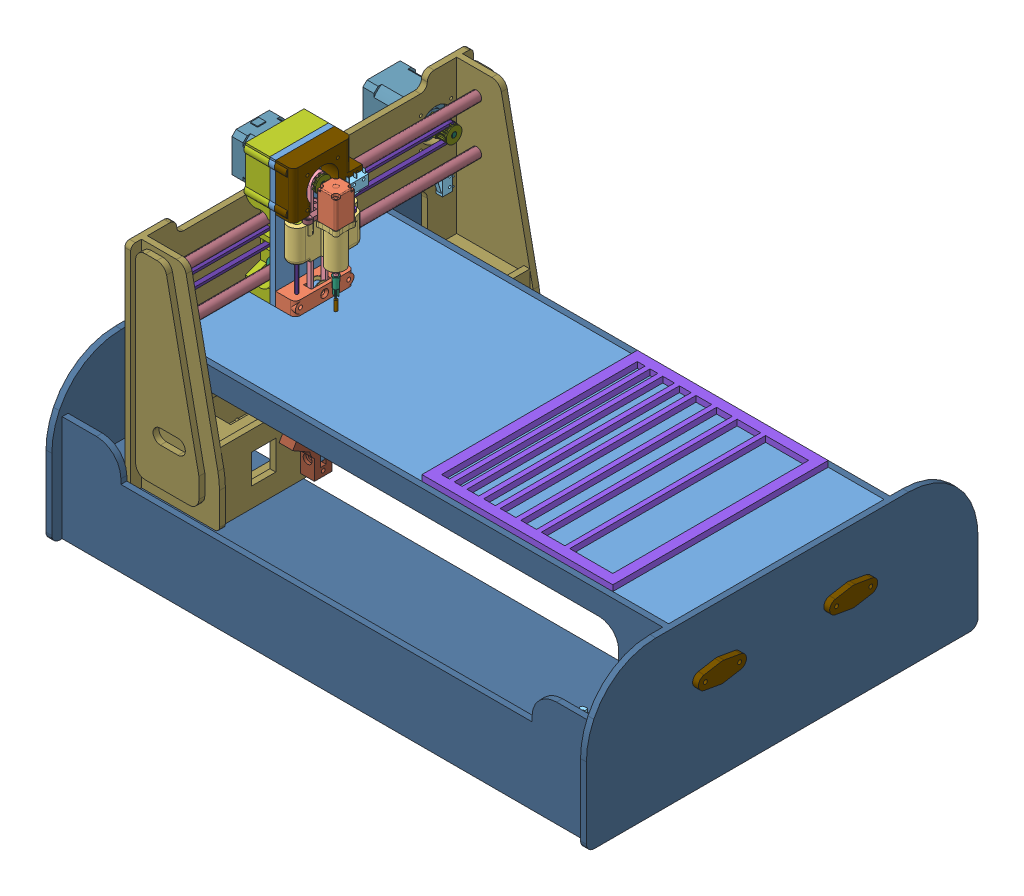
SolidWorks assembly Complete development assy, configuration По умолчанию. Lengths in mm.
Overall size (564 317.3 400).
83 component instances, 37 part files, 132 mates.
Components (placement in the parent):
- Y carret base-1: Y carret base [По умолчанию] at (-34.4349 94.3 -77.1214) x (0 0 -1) z (1 0 0) size (71.9 130 6)
- Vacuum manipulator-1: Vacuum manipulator [По умолчанию] at (13.1651 129.9 -77.1214) x (0 0 -1) z (1 0 0) size (60 110 38.83)
  - FL20STH30-0604A-1: FL20STH30-0604A [По умолчанию] at (0 10.1 -10.1) x (1 0 0) z (0 -1 0) size (20.2 20.2 45)
  - Vacuum connector-1: Vacuum connector [По умолчанию] at (0 -19.9 -10.1) x (1 0 0) z (0 0 -1) size (60 40 38.83)
  - Vacuum manipulator axis-1: Vacuum manipulator axis [По умолчанию] at (0 -39.1192 -10.1) x (0.991916 0 0.126893) z (-0.126893 0 0.991916) size (13 52.5 13)
  - Silicone gasket-1: Silicone gasket [По умолчанию] at (0 -39.9 -10.1) x (0.962843 0 -0.270063) z (0 1 0) size (13 13 5)
  - Silicone gasket-2: Silicone gasket [По умолчанию] at (0 -54.9 -10.1) x (0.992934 0 -0.118668) z (0 1 0) size (13 13 5)
  - Syringe needle-1: Syringe needle [По умолчанию] at (0 -68.4 -10.1) x (0.516653 0 0.856195) z (-0.856195 0 0.516653) size (6.5 31 6.5)
  - PTFE Z bushing-1: PTFE Z bushing [По умолчанию] at (-21 -53.9 -29.1) x (1 0 0) z (0 1 0) size (8 8 34)
  - PTFE Z bushing-2: PTFE Z bushing [По умолчанию] at (21 -53.9 -29.1) x (1 0 0) z (0 1 0) size (8 8 34)
  - Vacuum connectoe union-1: Vacuum connectoe union [По умолчанию] at (16 -7.4 -10.1) x (1 0 0) z (0 -1 0) size (7 7 25)
  - Silicone cap-1: Silicone cap [По умолчанию] at (0 -99.9 -10.1) x (1 0 0) z (0 1 0) size (3 3 10)
  - Vacoom connector fixing washer-2: Vacoom connector fixing washer [По умолчанию] at (0 -59.9 -10.1) x (0.897919 0 -0.440161) z (0 1 0) size (13 13 5)
  - Z belt spring-1: Z belt spring [По умолчанию] at (-7.25 -34.9 -29.1) x (0.706502 0 0.707711) z (0 -1 0) size (11.12 11.15 15.02)
  - Belt fixer-1: Belt fixer [По умолчанию] at (-7.25 -34.9 -29.1) x (-0.144268 0 -0.989539) z (0 1 0) size (11 11 15)
  - Vacoom connector cup-1: Vacoom connector cup [По умолчанию] at (-5.75 -15.9 -29.6632) x (1 0 0) z (0 -1 0) size (25.79 19.09 4)
- FL42-motor-1: FL42-motor [Default] at (-85.9269 135.15 -77.1214) x (0 0 -1) z (1 0 0) size (42.3 43.3 72)
  - FL42-1: FL42 [Default] at (-21.15 -21.15 3.992) size (42.3 43.3 49.5)
  - FL42-axis-1: FL42-axis [Default] at (0 0 31.992) size (5 5 44)
- belt pulley - hex base10-1: belt pulley - hex base10 [По умолчанию] at (-17.9349 135.15 -77.1214) x (0 0 -1) z (1 0 0) size (16 18.48 22.5)
- 3х86 rod-1: 3х86 rod [По умолчанию] at (-15.9349 122 -56.1214) x (0.06465 0 -0.997908) z (0 -1 0) size (3 3 86)
- 3х86 rod-2: 3х86 rod [По умолчанию] at (-15.9349 122 -98.1214) x (-0.993278 0 0.115757) z (0 -1 0) size (3 3 86)
- Z carret rod top fixer-1: Z carret rod top fixer [По умолчанию] at (-28.4349 131.8 -77.1214) x (0 0 -1) z (1 0 0) size (71.9 50 18)
- radial ball bearing_68_din-1: radial ball bearing_68_din [DIN 625 - 624 - 8,SI,NC,8_68] at (-15.9349 39.3 -77.1214) x (-1 0 0) z (0 -0.797158 -0.603771) size (5 13 13)
- Z carret rod bottom fixer-1: Z carret rod bottom fixer [По умолчанию] at (-28.4349 39.3 -77.1214) x (0 0 -1) z (1 0 0) size (60 14 20)
- Bearing washer-1: Bearing washer [По умолчанию] at (-11.9349 39.3 -77.1214) x (0 -0.383049 0.923728) z (-1 0 0) size (18 18 1.5)
- Bearing washer-2: Bearing washer [По умолчанию] at (-19.9349 39.3 -77.1214) x (0 0 -1) z (1 0 0) size (18 18 1.5)
- Z belt-1: Z belt [По умолчанию] at (-18.1849 89.225 -77.1214) x (0 0 -1) z (1 0 0) size (17 108.85 4.5)
- microswitch standin-1: microswitch standin [Default] at (-7.1849 127.3 -107.6214) x (1 0 0) z (0 0 -1) size (6.5 24.49 20.19)
- LM10UU-1: LM10UU [По умолчанию] at (-43.9349 51 -77.1214) x (-0.203502 -0.979074 0) z (-0.979074 0.203502 0) size (19 29 19)
- LM10UU-2: LM10UU [По умолчанию] at (-43.9349 101 -77.1214) x (-0.767518 0.641027 0) z (0.641027 0.767518 0) size (19 29 19)
- Y carret bearing fixer-1: Y carret bearing fixer [По умолчанию] at (-59.4349 97.3 -77.1214) x (0 0 -1) z (1 0 0) size (62.8 130 28)
- Cassete-1: Cassete [По умолчанию] at (292.0651 0 -110) x (0 0 -1) z (0 1 0) size (220 195 6)
- 16mm tube rod-1: 16mm tube rod [По умолчанию] at (426.0651 -58.2762 -177) x (0 -0.995748 -0.092117) z (-1 0 0) size (16 16 552)
- 16mm tube rod-2: 16mm tube rod [По умолчанию] at (426.0651 -58.2762 -43) x (0 0.422932 0.906162) z (-1 0 0) size (16 16 552)
- Base frame-1: Base frame [По умолчанию] at (204.0651 -12 -110) size (552 155 400)
- 16mm  printable linear bearing-1: 16mm  printable linear bearing [По умолчанию] at (-44.9682 -60.9468 -172.6484) x (0 0 1) z (1 0 0) size (62.22 53.88 14)
  - Bearing frame-1: Bearing frame [По умолчанию] at (-4.3516 -2.6706 55.2152) size (62.22 53.88 14)
  - radial ball bearing_68_din-1: radial ball bearing_68_din [DIN 625 - 624 - 8,SI,NC,8_68] at (-16.909 -9.9206 62.2152) x (0.5 -0.866025 0) z (0 0 1) size (5 13 13)
  - radial ball bearing_68_din-2: radial ball bearing_68_din [DIN 625 - 624 - 8,SI,NC,8_68] at (8.2057 -9.9206 62.2152) x (0.5 0.866025 0) z (0 0 1) size (5 13 13)
  - radial ball bearing_68_din-3: radial ball bearing_68_din [DIN 625 - 624 - 8,SI,NC,8_68] at (-4.3516 11.8294 62.2152) size (5 13 13)
- 16mm  printable linear bearing-2: 16mm  printable linear bearing [По умолчанию] at (-139.6501 -60.9468 -172.6484) x (0 0 1) z (1 0 0) size (62.22 53.88 14)
  - Bearing frame-1: Bearing frame [По умолчанию] at (-4.3516 -2.6706 55.2152) size (62.22 53.88 14)
  - radial ball bearing_68_din-1: radial ball bearing_68_din [DIN 625 - 624 - 8,SI,NC,8_68] at (-16.909 -9.9206 62.2152) x (0.5 -0.866025 0) z (0 0 1) size (5 13 13)
  - radial ball bearing_68_din-2: radial ball bearing_68_din [DIN 625 - 624 - 8,SI,NC,8_68] at (8.2057 -9.9206 62.2152) x (0.5 0.866025 0) z (0 0 1) size (5 13 13)
  - radial ball bearing_68_din-3: radial ball bearing_68_din [DIN 625 - 624 - 8,SI,NC,8_68] at (-4.3516 11.8294 62.2152) size (5 13 13)
- 16mm  printable linear bearing-3: 16mm  printable linear bearing [По умолчанию] at (-44.9682 -60.9468 -38.6484) x (0 0 1) z (1 0 0) size (62.22 53.88 14)
  - Bearing frame-1: Bearing frame [По умолчанию] at (-4.3516 -2.6706 55.2152) size (62.22 53.88 14)
  - radial ball bearing_68_din-1: radial ball bearing_68_din [DIN 625 - 624 - 8,SI,NC,8_68] at (-16.909 -9.9206 62.2152) x (0.5 -0.866025 0) z (0 0 1) size (5 13 13)
  - radial ball bearing_68_din-2: radial ball bearing_68_din [DIN 625 - 624 - 8,SI,NC,8_68] at (8.2057 -9.9206 62.2152) x (0.5 0.866025 0) z (0 0 1) size (5 13 13)
  - radial ball bearing_68_din-3: radial ball bearing_68_din [DIN 625 - 624 - 8,SI,NC,8_68] at (-4.3516 11.8294 62.2152) size (5 13 13)
- 16mm  printable linear bearing-4: 16mm  printable linear bearing [По умолчанию] at (-139.6501 -60.9468 -38.6484) x (0 0 1) z (1 0 0) size (62.22 53.88 14)
  - Bearing frame-1: Bearing frame [По умолчанию] at (-4.3516 -2.6706 55.2152) size (62.22 53.88 14)
  - radial ball bearing_68_din-1: radial ball bearing_68_din [DIN 625 - 624 - 8,SI,NC,8_68] at (-16.909 -9.9206 62.2152) x (0.5 -0.866025 0) z (0 0 1) size (5 13 13)
  - radial ball bearing_68_din-2: radial ball bearing_68_din [DIN 625 - 624 - 8,SI,NC,8_68] at (8.2057 -9.9206 62.2152) x (0.5 0.866025 0) z (0 0 1) size (5 13 13)
  - radial ball bearing_68_din-3: radial ball bearing_68_din [DIN 625 - 624 - 8,SI,NC,8_68] at (-4.3516 11.8294 62.2152) size (5 13 13)
- X carret-3: X carret [По умолчанию] at (-70.4349 -95 60) x (0 0 -1) z (1 0 0) size (350 220 85.68)
- FL42-motor-2: FL42-motor [Default] at (-121.9269 76 -246.85) x (0 0 1) z (1 0 0) size (42.3 43.3 72)
  - FL42-1: FL42 [Default] at (-21.15 -21.15 3.992) size (42.3 43.3 49.5)
  - FL42-axis-1: FL42-axis [Default] at (0 0 31.992) size (5 5 44)
- 10mm bar-1: 10mm bar [По умолчанию] at (-43.9349 101 -274) size (10 10 328)
- 10mm bar-2: 10mm bar [По умолчанию] at (-43.9349 51 -274) size (10 10 328)
- FL42-motor-3: FL42-motor [Default] at (398.9151 -127.992 -110) x (1 0 0) z (0 1 0) size (42.3 43.3 72)
  - FL42-1: FL42 [Default] at (-21.15 -21.15 3.992) size (42.3 43.3 49.5)
  - FL42-axis-1: FL42-axis [Default] at (0 0 31.992) size (5 5 44)
- belt pulley - hex base10-3: belt pulley - hex base10 [По умолчанию] at (398.9151 -60 -110) x (-1 0 0) z (0 1 0) size (16 18.48 22.5)
- PSU standin-1: PSU standin [Default] at (-69.9349 -129 -244.65) x (0 0 -1) z (1 0 0) size (97.7 50 200)
- Belt idler-1: Belt idler [По умолчанию] at (-64.4349 76 33.15) x (0 -1 0) z (1 0 0) size (30 16 9.9)
- Belt idler-2: Belt idler [По умолчанию] at (-92.9349 -70.5 -110) x (0 0 -1) z (0 1 0) size (30 16 9.9)
- Bearing washer-3: Bearing washer [По умолчанию] at (-92.9349 -54.1 -110) x (-0.383049 0 -0.923728) z (0 -1 0) size (18 18 1.5)
- Bearing washer-4: Bearing washer [По умолчанию] at (-48.0349 76 33.15) x (0 0.383049 -0.923728) z (-1 0 0) size (18 18 1.5)
- radial ball bearing_68_din-2: radial ball bearing_68_din [DIN 625 - 624 - 8,SI,NC,8_68] at (-52.0349 76 33.15) size (5 13 13)
- radial ball bearing_68_din-3: radial ball bearing_68_din [DIN 625 - 624 - 8,SI,NC,8_68] at (-92.9349 -58.1 -110) x (0 1 0) z (0 0 1) size (5 13 13)
- X belt-1: X belt [По умолчанию] at (152.9901 -55.85 -110) x (0 0 1) z (0 -1 0) size (17 508.85 4.5)
- belt pulley - hex base10-4: belt pulley - hex base10 [По умолчанию] at (-53.9349 76 -246.85) x (0 0 -1) z (1 0 0) size (16 18.48 22.5)
- Y belt-2: Y belt [По умолчанию] at (-49.7849 76 -106.85) x (0 -1 0) z (-1 0 0) size (17 297 4.5)
- X rod fixer-1: X rod fixer [По умолчанию] at (426.0651 -58.2762 -43) x (0 0 -1) z (1 0 0) size (49 20 6)
- X rod fixer-2: X rod fixer [По умолчанию] at (426.0651 -58.2762 -177) x (0 0 -1) z (1 0 0) size (49 20 6)
- X rod fixer-3: X rod fixer [По умолчанию] at (-125.9349 -58.2762 -177) x (0 0 1) z (-1 0 0) size (49 20 6)
- X rod fixer-4: X rod fixer [По умолчанию] at (-125.9349 -58.2762 -43) x (0 0 1) z (-1 0 0) size (49 20 6)
- microswitch standin-2: microswitch standin [Default] at (-61.1849 25 -257) x (1 0 0) z (0 -1 0) size (6.5 24.49 20.19)
- microswitch standin-3: microswitch standin [Default] at (376.0651 -94.75 33.5) x (0 1 0) z (0 0 1) size (6.5 24.49 20.19)
- Top plate-1: Top plate [По умолчанию] at (150.0651 0 -110) x (1 0 0) z (0 -1 0) size (540 220 6)
Mates (geometry in assembly coordinates):
- Расстояние2: distance = 3.5 mm anti-aligned: plane of Vacuum manipulator-1/Vacuum connector-1 through (-24.9349 50.5442 -78.8714) normal (-1 0 0); plane of Y carret base-1 through (-28.4349 94.3 -77.1214) normal (1 0 0)
- Ширина1: width anti-aligned: plane of Y carret base-1 through (-28.4349 32.3 -47.1214) normal (0 0 1); plane of Y carret base-1 through (-28.4349 32.3 -107.1214) normal (0 0 -1); cylinder of Vacuum manipulator-1/Vacuum connector-1 through (3.0651 138.2843 -77.1214) axis (0 -1 0) radius 9
- Совпадение4: coincident anti-aligned: plane of Y carret base-1 through (-34.4349 94.3 -77.1214) normal (-1 0 0); plane of FL42-motor-1/FL42-1 through (-34.4349 156.3 -55.9714) normal (1 0 0)
- Ширина2: width anti-aligned: plane of FL42-motor-1/FL42-1 through (-34.4349 114 -55.9714) normal (0 0 1); plane of FL42-motor-1/FL42-1 through (-34.4349 114 -98.2714) normal (0 0 -1); plane of Y carret base-1 through (-28.4349 32.3 -107.1214) normal (0 0 -1); plane of Y carret base-1 through (-28.4349 32.3 -47.1214) normal (0 0 1)
- Совпадение5: coincident anti-aligned: plane of FL42-motor-1/FL42-1 through (-32.4349 135.15 -77.1214) normal (1 0 0); plane of belt pulley - hex base10-1 through (-32.4349 144.3876 -77.1214) normal (-1 0 0)
- Концентричный1: concentric anti-aligned: cylinder of FL42-motor-1/FL42-axis-1 through (-9.9349 135.15 -77.1214) axis (-1 0 0) radius 2.5; cylinder of belt pulley - hex base10-1 through (-39.9302 135.15 -77.1214) axis (1 0 0) radius 2.65
- Параллельность2: parallel anti-aligned: plane of FL42-motor-1/FL42-axis-1 through (-29.9349 137.15 -78.6214) normal (0 0 -1); plane of belt pulley - hex base10-1 through (-32.4349 130.5312 -69.1214) normal (0 0 1)
- Расстояние10: distance = 6 mm aligned: plane of FL42-motor-1/FL42-1 through (-34.4349 156.3 -55.9714) normal (0 1 0); plane of Y carret base-1 through (-34.4349 162.3 -77.1214) normal (0 1 0)
- Концентричный2: concentric anti-aligned: cylinder of Vacuum manipulator-1/PTFE Z bushing-2 through (-15.9349 110 -98.1214) axis (0 -1 0) radius 1.5; cylinder of 3х86 rod-2 through (-15.9349 36 -98.1214) axis (0 1 0) radius 1.5
- Концентричный3: concentric anti-aligned: cylinder of Vacuum manipulator-1/PTFE Z bushing-1 through (-15.9349 110 -56.1214) axis (0 -1 0) radius 1.5; cylinder of 3х86 rod-1 through (-15.9349 36 -56.1214) axis (0 1 0) radius 1.5
- Совпадение11: coincident aligned: plane of 3х86 rod-1 through (-15.9349 122 -56.1214) normal (0 1 0); plane of 3х86 rod-2 through (-15.9349 122 -98.1214) normal (0 1 0)
- Совпадение13: coincident aligned: plane of Y carret base-1 through (-28.4349 32.3 -47.1214) normal (0 0 1); plane of Z carret rod top fixer-1 through (-10.4349 131.8 -47.1214) normal (0 0 1)
- Совпадение15: coincident anti-aligned: plane of Y carret base-1 through (-28.4349 94.3 -77.1214) normal (1 0 0); plane of Z carret rod top fixer-1 through (-28.4349 131.8 -77.1214) normal (-1 0 0)
- Совпадение16: coincident anti-aligned: plane of 3х86 rod-2 through (-15.9349 122 -98.1214) normal (0 1 0); plane of Z carret rod top fixer-1 through (-15.9349 122 -98.1214) normal (0 -1 0)
- Параллельность3: parallel anti-aligned: plane of Y carret base-1 through (-28.4349 94.3 -77.1214) normal (1 0 0); plane of radial ball bearing_68_din-1 through (-18.4349 43.1038 -82.1435) normal (-1 0 0)
- Ширина4: width anti-aligned: plane of Y carret base-1 through (-28.4349 32.3 -107.1214) normal (0 0 -1); plane of Y carret base-1 through (-28.4349 32.3 -47.1214) normal (0 0 1); cylinder of radial ball bearing_68_din-1 through (4.7026 39.3 -77.1214) axis (-1 0 0) radius 6.5
- Совпадение18: coincident anti-aligned: plane of Y carret base-1 through (-28.4349 94.3 -77.1214) normal (1 0 0); plane of Z carret rod bottom fixer-1 through (-28.4349 39.3 -77.1214) normal (-1 0 0)
- Совпадение19: coincident aligned: plane of Y carret base-1 through (-28.4349 32.3 -107.1214) normal (0 -1 0); plane of Z carret rod bottom fixer-1 through (-8.4349 32.3 -107.1214) normal (0 -1 0)
- Совпадение20: coincident aligned: plane of Y carret base-1 through (-28.4349 32.3 -47.1214) normal (0 0 1); plane of Z carret rod bottom fixer-1 through (-8.4349 32.3 -47.1214) normal (0 0 1)
- Расстояние3: distance = 10 mm anti-aligned: plane of radial ball bearing_68_din-1 through (-18.4349 43.1038 -82.1435) normal (-1 0 0); plane of Y carret base-1 through (-28.4349 94.3 -77.1214) normal (1 0 0)
- Совпадение22: coincident anti-aligned: plane of radial ball bearing_68_din-1 through (-13.4349 41.3226 -79.7919) normal (1 0 0); plane of Bearing washer-1 through (-13.4349 39.3 -77.1214) normal (-1 0 0)
- Концентричный4: concentric anti-aligned: cylinder of radial ball bearing_68_din-1 through (4.7026 39.3 -77.1214) axis (-1 0 0) radius 2; cylinder of Bearing washer-1 through (-13.2349 39.3 -77.1214) axis (1 0 0) radius 2
- Совпадение24: coincident anti-aligned: plane of radial ball bearing_68_din-1 through (-18.4349 40.6283 -78.8751) normal (-1 0 0); plane of Bearing washer-2 through (-18.4349 39.3 -77.1214) normal (1 0 0)
- Концентричный5: concentric aligned: cylinder of radial ball bearing_68_din-1 through (4.7026 39.3 -77.1214) axis (-1 0 0) radius 2; cylinder of Bearing washer-2 through (-18.6349 39.3 -77.1214) axis (-1 0 0) radius 2
- Граничное расстояние1: limit distance = 29.7 mm anti-aligned: plane of Z carret rod bottom fixer-1 through (-8.4349 46.3 -107.1214) normal (0 1 0); plane of Vacuum manipulator-1/Vacuum connector-1 through (-24.9349 76 -47.1214) normal (0 -1 0)
- Ширина5: width anti-aligned: plane of Z carret rod bottom fixer-1 through (-8.4349 32.3 -107.1214) normal (0 -1 0); plane of Z carret rod bottom fixer-1 through (-8.4349 46.3 -107.1214) normal (0 1 0); cylinder of radial ball bearing_68_din-1 through (4.7026 39.3 -77.1214) axis (-1 0 0) radius 6.5
- Концентричный6: concentric aligned: cylinder of belt pulley - hex base10-1 through (-9.9349 135.15 -77.1214) axis (-1 0 0) radius 8; cylinder of Z belt-1 through (-13.6849 135.15 -77.1214) axis (-1 0 0) radius 6
- Ширина6: width anti-aligned: plane of Z belt-1 through (-13.6849 43.3 -77.1214) normal (1 0 0); plane of Z belt-1 through (-18.1849 43.3 -77.1214) normal (-1 0 0); plane of radial ball bearing_68_din-1 through (-18.4349 43.1038 -82.1435) normal (-1 0 0); plane of radial ball bearing_68_din-1 through (-13.4349 42.4094 -81.2268) normal (1 0 0)
- Совпадение25: coincident anti-aligned: plane of Z carret rod top fixer-1 through (-10.4349 131.8 -77.1214) normal (1 0 0); plane of microswitch standin-1 through (-10.4349 117.3 -117.6214) normal (-1 0 0)
- Параллельность4: parallel anti-aligned: plane of Z carret rod top fixer-1 through (-10.4349 131.8 -107.1214) normal (0 0 -1); plane of microswitch standin-1 through (-3.9349 117.3 -97.6214) normal (0 0 1)
- Расстояние5: distance = 2 mm anti-aligned: plane of microswitch standin-1 through (-3.9349 117.3 -97.6214) normal (0 0 1); cylinder of Z carret rod top fixer-1 through (-14.4349 119.65 -92.6214) axis (1 0 0) radius 3
- Расстояние6: distance = 35 mm aligned: plane of microswitch standin-1 through (-10.4349 127.3 -97.6214) normal (0 1 0); plane of Z carret rod top fixer-1 through (-28.4349 162.3 -77.1214) normal (0 1 0)
- Совпадение26: coincident aligned: plane of LM10UU-1 through (-42.0016 60.3012 -62.6214) normal (0 0 1); plane of LM10UU-2 through (-36.6434 94.9102 -62.6214) normal (0 0 1)
- Касательность1: tangent anti-aligned: plane of Y carret base-1 through (-34.4349 94.3 -77.1214) normal (-1 0 0); cylinder of LM10UU-1 through (-43.9349 51 -62.6214) axis (0 0 1) radius 9.5
- Касательность2: tangent anti-aligned: plane of Y carret base-1 through (-34.4349 94.3 -77.1214) normal (-1 0 0); cylinder of LM10UU-2 through (-43.9349 101 -62.6214) axis (0 0 1) radius 9.5
- Параллельность5: parallel anti-aligned: plane of Y carret base-1 through (-28.4349 32.3 -107.1214) normal (0 0 -1); plane of LM10UU-2 through (-36.6434 94.9102 -62.6214) normal (0 0 1)
- Ширина7: width anti-aligned: plane of LM10UU-2 through (-40.0973 97.7949 -91.6214) normal (0 0 -1); plane of LM10UU-2 through (-36.6434 94.9102 -62.6214) normal (0 0 1); plane of Y carret base-1 through (-28.4349 32.3 -47.1214) normal (0 0 1); plane of Y carret base-1 through (-28.4349 32.3 -107.1214) normal (0 0 -1)
- Расстояние8: distance = 3.5 mm anti-aligned: cylinder of LM10UU-2 through (-43.9349 101 -62.6214) axis (0 0 1) radius 9.5; plane of FL42-motor-1/FL42-1 through (-34.4349 114 -55.9714) normal (0 -1 0)
- Совпадение29: coincident aligned: plane of Y carret base-1 through (-28.4349 32.3 -107.1214) normal (0 -1 0); plane of Y carret bearing fixer-1 through (-34.4349 32.3 -107.1214) normal (0 -1 0)
- Совпадение30: coincident aligned: plane of Y carret base-1 through (-28.4349 32.3 -107.1214) normal (0 0 -1); plane of Y carret bearing fixer-1 through (-34.4349 32.3 -107.1214) normal (0 0 -1)
- Совпадение31: coincident anti-aligned: plane of Y carret base-1 through (-34.4349 94.3 -77.1214) normal (-1 0 0); plane of Y carret bearing fixer-1 through (-34.4349 97.3 -77.1214) normal (1 0 0)
- Совпадение32: coincident aligned: plane of Y carret base-1 through (-34.4349 162.3 -77.1214) normal (0 1 0); plane of Z carret rod top fixer-1 through (-28.4349 162.3 -77.1214) normal (0 1 0)
- Расстояние11: distance = 40 mm: cylinder of LM10UU-1 through (-43.9349 51 -62.6214) axis (0 0 1) radius 5; cylinder of LM10UU-2 through (-43.9349 101 -62.6214) axis (0 0 1) radius 5
- Параллельность6: parallel aligned: plane of Y carret base-1 through (-28.4349 94.3 -77.1214) normal (1 0 0); plane of assembly through (0 0 0) normal (1 0 0)
- Совпадение39: coincident aligned: plane of 16mm tube rod-1 through (-125.9349 -58.2762 -177) normal (-1 0 0); plane of 16mm tube rod-2 through (-125.9349 -58.2762 -43) normal (-1 0 0)
- Параллельность7: parallel anti-aligned: plane of Cassete-1 through (363.0651 6 -220) normal (1 0 0); plane of 16mm tube rod-2 through (-125.9349 -58.2762 -43) normal (-1 0 0)
- Симметричный1: symmetric aligned: cylinder of 16mm tube rod-1 through (-125.9349 -58.2762 -177) axis (1 0 0) radius 8; cylinder of 16mm tube rod-2 through (-125.9349 -58.2762 -43) axis (1 0 0) radius 8; plane of assembly through (0 0 -110) normal (0 0 1)
- Расстояние12: distance = 32.3 mm anti-aligned: plane of Y carret bearing fixer-1 through (-34.4349 32.3 -107.1214) normal (0 -1 0); plane of Top plate-1 through (150.0651 0 -110) normal (0 1 0)
- Концентричный8: concentric aligned: cylinder of 16mm  printable linear bearing-3/Bearing frame-1 through (24.247 -58.2762 -43) axis (-1 0 0) radius 8.5; cylinder of 16mm  printable linear bearing-4/Bearing frame-1 through (-70.4349 -58.2762 -43) axis (-1 0 0) radius 8.5
- Совпадение44: coincident aligned: plane of 16mm  printable linear bearing-3/Bearing frame-1 through (24.247 -89 -43) normal (0 -1 0); plane of 16mm  printable linear bearing-4/Bearing frame-1 through (-70.4349 -89 -43) normal (0 -1 0)
- Концентричный9: concentric aligned: cylinder of 16mm  printable linear bearing-1/Bearing frame-1 through (24.247 -58.2762 -177) axis (-1 0 0) radius 8.5; cylinder of 16mm  printable linear bearing-2/Bearing frame-1 through (-70.4349 -58.2762 -177) axis (-1 0 0) radius 8.5
- Совпадение45: coincident aligned: plane of 16mm  printable linear bearing-1/Bearing frame-1 through (24.247 -89 -177) normal (0 -1 0); plane of 16mm  printable linear bearing-2/Bearing frame-1 through (-70.4349 -89 -177) normal (0 -1 0)
- Концентричный10: concentric anti-aligned: cylinder of 16mm tube rod-1 through (-125.9349 -58.2762 -177) axis (1 0 0) radius 8; cylinder of 16mm  printable linear bearing-1/Bearing frame-1 through (24.247 -58.2762 -177) axis (-1 0 0) radius 8.5
- Параллельность8: parallel anti-aligned: plane of Base frame-1 through (204.0651 -12 -110) normal (0 1 0); plane of 16mm  printable linear bearing-1/Bearing frame-1 through (24.247 -89 -177) normal (0 -1 0)
- Концентричный11: concentric anti-aligned: cylinder of 16mm tube rod-2 through (-125.9349 -58.2762 -43) axis (1 0 0) radius 8; cylinder of 16mm  printable linear bearing-3/Bearing frame-1 through (24.247 -58.2762 -43) axis (-1 0 0) radius 8.5
- Параллельность9: parallel anti-aligned: plane of Base frame-1 through (204.0651 -12 -110) normal (0 1 0); plane of 16mm  printable linear bearing-3/Bearing frame-1 through (24.247 -89 -43) normal (0 -1 0)
- Совпадение48: coincident aligned: plane of 16mm  printable linear bearing-1/Bearing frame-1 through (24.247 -58.2762 -177) normal (1 0 0); plane of 16mm  printable linear bearing-3/Bearing frame-1 through (24.247 -58.2762 -43) normal (1 0 0)
- Совпадение49: coincident aligned: plane of 16mm  printable linear bearing-2/Bearing frame-1 through (-70.4349 -58.2762 -177) normal (1 0 0); plane of 16mm  printable linear bearing-4/Bearing frame-1 through (-70.4349 -58.2762 -43) normal (1 0 0)
- Расстояние14: distance = 83 mm aligned: plane of Base frame-1 through (204.0651 -12 -110) normal (0 -1 0); plane of X carret-3 through (-70.4349 -95 -280) normal (0 -1 0)
- Расстояние15: distance = 5 mm anti-aligned: plane of Y carret bearing fixer-1 through (-59.4349 97.3 -77.1214) normal (-1 0 0); plane of X carret-3 through (-64.4349 -423.2941 48) normal (1 0 0)
- Расстояние16: distance = 120 mm: cylinder of 16mm tube rod-2 through (-125.9349 -58.2762 -43) axis (1 0 0) radius 7; cylinder of 16mm tube rod-1 through (-125.9349 -58.2762 -177) axis (1 0 0) radius 7
- Совпадение62: coincident anti-aligned: plane of 16mm  printable linear bearing-4/Bearing frame-1 through (-70.4349 -58.2762 -43) normal (1 0 0); plane of X carret-3 through (-70.4349 125 -280) normal (-1 0 0)
- Совпадение67: coincident anti-aligned: plane of X carret-3 through (-70.4349 125 -280) normal (-1 0 0); plane of FL42-motor-2/FL42-1 through (-70.4349 54.85 -268) normal (1 0 0)
- Ширина11: width aligned: plane of X carret-3 through (-70.4349 -95 -280) normal (0 0 -1); plane of X carret-3 through (-70.4349 -95 60) normal (0 0 1); plane of Base frame-1 through (-40.5705 -23 -226) normal (0 0 -1); plane of Base frame-1 through (-40.5705 -23 6) normal (0 0 1)
- Совпадение71: coincident aligned: plane of 10mm bar-1 through (-43.9349 101 54) normal (0 0 1); plane of 10mm bar-2 through (-43.9349 51 54) normal (0 0 1)
- Совпадение72: coincident anti-aligned: plane of X carret-3 through (-43.9349 101 54) normal (0 0 -1); plane of 10mm bar-1 through (-43.9349 101 54) normal (0 0 1)
- Концентричный14: concentric anti-aligned: cylinder of X carret-3 through (-43.9349 101 -294.1421) axis (0 0 1) radius 5; cylinder of 10mm bar-1 through (-43.9349 101 54) axis (0 0 -1) radius 5
- Концентричный15: concentric anti-aligned: cylinder of X carret-3 through (-43.9349 51 -294.1421) axis (0 0 1) radius 5; cylinder of 10mm bar-2 through (-43.9349 51 54) axis (0 0 -1) radius 5
- Совпадение75: coincident aligned: plane of 16mm tube rod-2 through (-125.9349 -58.2762 -43) normal (-1 0 0); plane of Base frame-1 through (-125.9349 -12 -110) normal (-1 0 0)
- Концентричный16: concentric anti-aligned: cylinder of FL42-motor-3/FL42-axis-1 through (398.9151 -52 -110) axis (0 -1 0) radius 2.5; cylinder of belt pulley - hex base10-3 through (398.9151 -81.9953 -110) axis (0 1 0) radius 2.65
- Параллельность11: parallel aligned: plane of FL42-motor-3/FL42-axis-1 through (400.4151 -72 -112) normal (1 0 0); plane of belt pulley - hex base10-3 through (406.9151 -74.5 -114.6188) normal (1 0 0)
- Совпадение77: coincident anti-aligned: plane of FL42-motor-3/FL42-1 through (398.9151 -74.5 -110) normal (0 1 0); plane of belt pulley - hex base10-3 through (398.9151 -74.5 -100.7624) normal (0 -1 0)
- Ширина12: width anti-aligned: plane of FL42-motor-3/FL42-1 through (377.7651 -76.5 -88.85) normal (0 0 1); plane of FL42-motor-3/FL42-1 through (377.7651 -76.5 -131.15) normal (0 0 -1); plane of Base frame-1 through (-228.1014 -155 73.5) normal (0 0 -1); plane of Base frame-1 through (-228.1014 -155 -293.5) normal (0 0 1)
- Граничное расстояние2: limit distance = 49.5 mm anti-aligned: plane of X carret-3 through (-70.4349 125 -280) normal (-1 0 0); plane of Base frame-1 through (-119.9349 -12 -110) normal (1 0 0)
- Расстояние23: distance = 50 mm anti-aligned: plane of Base frame-1 through (-119.9349 -12 -110) normal (1 0 0); plane of PSU standin-1 through (-69.9349 -154 -195.8) normal (-1 0 0)
- Совпадение83: coincident anti-aligned: plane of Base frame-1 through (-228.1014 -155 -293.5) normal (0 0 1); plane of PSU standin-1 through (130.0651 -104 -293.5) normal (0 0 -1)
- Совпадение84: coincident anti-aligned: plane of Base frame-1 through (787.1142 -104 -293.5) normal (0 -1 0); plane of PSU standin-1 through (130.0651 -104 -293.5) normal (0 1 0)
- Совпадение85: coincident anti-aligned: plane of 16mm  printable linear bearing-3/Bearing frame-1 through (10.247 -58.2762 -43) normal (-1 0 0); plane of X carret-3 through (10.247 -95 48) normal (1 0 0)
- Совпадение86: coincident aligned: plane of 16mm  printable linear bearing-3/Bearing frame-1 through (24.247 -89 -43) normal (0 -1 0); plane of X carret-3 through (-389.7654 -89 -268) normal (0 -1 0)
- Совпадение87: coincident anti-aligned: plane of Base frame-1 through (420.0651 -12 -110) normal (-1 0 0); plane of FL42-motor-3/FL42-1 through (420.0651 -76.5 -88.85) normal (1 0 0)
- Расстояние20: distance = 20 mm aligned: plane of FL42-motor-3/FL42-1 through (377.7651 -124 -131.15) normal (0 -1 0); plane of Base frame-1 through (787.1142 -104 -293.5) normal (0 -1 0)
- Концентричный17: concentric anti-aligned: cylinder of Belt idler-2 through (-92.9349 -61.6 -110) axis (0 -1 0) radius 2; cylinder of radial ball bearing_68_din-3 through (-92.9349 -78.7375 -110) axis (0 1 0) radius 2
- Совпадение89: coincident anti-aligned: plane of Belt idler-2 through (-92.9349 -60.6 -108) normal (0 1 0); plane of radial ball bearing_68_din-3 through (-96.2849 -60.6 -110) normal (0 -1 0)
- Концентричный18: concentric aligned: cylinder of Bearing washer-3 through (-92.9349 -55.4 -110) axis (0 1 0) radius 2; cylinder of radial ball bearing_68_din-3 through (-92.9349 -78.7375 -110) axis (0 1 0) radius 2
- Совпадение90: coincident anti-aligned: plane of Bearing washer-3 through (-92.9349 -55.6 -110) normal (0 -1 0); plane of radial ball bearing_68_din-3 through (-95.1349 -55.6 -110) normal (0 1 0)
- Концентричный19: concentric anti-aligned: cylinder of Belt idler-1 through (-55.5349 76 33.15) axis (-1 0 0) radius 2; cylinder of radial ball bearing_68_din-2 through (-72.6724 76 33.15) axis (1 0 0) radius 2
- Совпадение91: coincident anti-aligned: plane of Belt idler-1 through (-54.5349 78 33.15) normal (1 0 0); plane of radial ball bearing_68_din-2 through (-54.5349 79.35 33.15) normal (-1 0 0)
- Концентричный20: concentric anti-aligned: cylinder of Belt idler-1 through (-55.5349 76 33.15) axis (-1 0 0) radius 2; cylinder of Bearing washer-4 through (-49.3349 76 33.15) axis (1 0 0) radius 2
- Совпадение92: coincident anti-aligned: plane of Bearing washer-4 through (-49.5349 76 33.15) normal (-1 0 0); plane of radial ball bearing_68_din-2 through (-49.5349 78.2 33.15) normal (1 0 0)
- Совпадение93: coincident anti-aligned: plane of X carret-3 through (-64.4349 -423.2941 48) normal (1 0 0); plane of Belt idler-1 through (-64.4349 91 25.15) normal (-1 0 0)
- Ширина13: width anti-aligned: plane of Belt idler-1 through (-55.5349 61 41.15) normal (0 -1 0); plane of Belt idler-1 through (-55.5349 91 41.15) normal (0 1 0); plane of FL42-motor-2/FL42-1 through (-70.4349 97.15 -268) normal (0 1 0); plane of FL42-motor-2/FL42-1 through (-70.4349 54.85 -268) normal (0 -1 0)
- Ширина14: width anti-aligned: plane of Belt idler-2 through (-84.9349 -61.6 -95) normal (0 0 1); plane of Belt idler-2 through (-84.9349 -61.6 -125) normal (0 0 -1); plane of FL42-motor-3/FL42-1 through (377.7651 -76.5 -131.15) normal (0 0 -1); plane of FL42-motor-3/FL42-1 through (377.7651 -76.5 -88.85) normal (0 0 1)
- Совпадение94: coincident anti-aligned: plane of Base frame-1 through (375.0651 -70.5 -220) normal (0 1 0); plane of Belt idler-2 through (-100.9349 -70.5 -95) normal (0 -1 0)
- Совпадение95: coincident aligned: plane of Base frame-1 through (-84.9349 -12 -110) normal (1 0 0); plane of Belt idler-2 through (-84.9349 -61.6 -125) normal (1 0 0)
- Граничное расстояние3: limit distance = 95.1214 mm anti-aligned: plane of Y carret base-1 through (-28.4349 32.3 -47.1214) normal (0 0 1); plane of X carret-3 through (24.5651 -423.2941 48) normal (0 0 -1)
- Концентричный21: concentric anti-aligned: cylinder of belt pulley - hex base10-3 through (398.9151 -52 -110) axis (0 -1 0) radius 8; cylinder of X belt-1 through (398.9151 -60.35 -110) axis (0 1 0) radius 6
- Концентричный22: concentric aligned: cylinder of radial ball bearing_68_din-3 through (-92.9349 -78.7375 -110) axis (0 1 0) radius 6.5; cylinder of X belt-1 through (-92.9349 -60.35 -110) axis (0 1 0) radius 8.5
- Ширина15: width aligned: plane of X belt-1 through (398.9151 -55.85 -110) normal (0 1 0); plane of X belt-1 through (398.9151 -60.35 -110) normal (0 -1 0); plane of radial ball bearing_68_din-3 through (-99.2349 -55.6 -110) normal (0 1 0); plane of radial ball bearing_68_din-3 through (-98.0849 -60.6 -110) normal (0 -1 0)
- Концентричный26: concentric anti-aligned: cylinder of FL42-motor-2/FL42-axis-1 through (-45.9349 76 -246.85) axis (-1 0 0) radius 2.5; cylinder of belt pulley - hex base10-4 through (-75.9302 76 -246.85) axis (1 0 0) radius 2.65
- Совпадение99: coincident anti-aligned: plane of FL42-motor-2/FL42-1 through (-68.4349 76 -246.85) normal (1 0 0); plane of belt pulley - hex base10-4 through (-68.4349 85.2376 -246.85) normal (-1 0 0)
- Параллельность14: parallel aligned: plane of FL42-motor-2/FL42-axis-1 through (-65.9349 74 -245.35) normal (0 0 1); plane of belt pulley - hex base10-4 through (-68.4349 71.3812 -238.85) normal (0 0 1)
- Ширина17: width anti-aligned: plane of radial ball bearing_68_din-2 through (-49.5349 82.3 33.15) normal (1 0 0); plane of radial ball bearing_68_din-2 through (-54.5349 81.15 33.15) normal (-1 0 0); plane of Y belt-2 through (-54.2849 76 -246.85) normal (-1 0 0); plane of Y belt-2 through (-49.7849 76 -246.85) normal (1 0 0)
- Концентричный27: concentric aligned: cylinder of radial ball bearing_68_din-2 through (-72.6724 76 33.15) axis (1 0 0) radius 6.5; cylinder of Y belt-2 through (-54.2849 76 33.15) axis (1 0 0) radius 8.5
- Концентричный29: concentric anti-aligned: cylinder of belt pulley - hex base10-4 through (-45.9349 76 -246.85) axis (-1 0 0) radius 8; cylinder of Y belt-2 through (-54.2849 76 -246.85) axis (1 0 0) radius 8.5
- Совпадение100: coincident aligned: plane of X rod fixer-1 through (426.0651 -58.2762 -43) normal (-1 0 0); plane of X rod fixer-2 through (426.0651 -58.2762 -177) normal (-1 0 0)
- Совпадение101: coincident anti-aligned: plane of Base frame-1 through (426.0651 -12 -110) normal (1 0 0); plane of X rod fixer-2 through (426.0651 -58.2762 -177) normal (-1 0 0)
- Совпадение102: coincident aligned: plane of X rod fixer-3 through (-125.9349 -58.2762 -177) normal (1 0 0); plane of X rod fixer-4 through (-125.9349 -58.2762 -43) normal (1 0 0)
- Совпадение103: coincident anti-aligned: plane of Base frame-1 through (-125.9349 -12 -110) normal (-1 0 0); plane of X rod fixer-4 through (-125.9349 -58.2762 -43) normal (1 0 0)
- Концентричный37: concentric anti-aligned: cylinder of Base frame-1 through (-125.9349 -58.2762 -25.5) axis (1 0 0) radius 1; cylinder of X rod fixer-1 through (432.0651 -58.2762 -25.5) axis (-1 0 0) radius 2
- Концентричный38: concentric anti-aligned: cylinder of Base frame-1 through (-125.9349 -58.2762 -60.5) axis (1 0 0) radius 1; cylinder of X rod fixer-1 through (432.0651 -58.2762 -60.5) axis (-1 0 0) radius 2
- Концентричный39: concentric anti-aligned: cylinder of Base frame-1 through (-125.9349 -58.2762 -194.5) axis (1 0 0) radius 1; cylinder of X rod fixer-2 through (432.0651 -58.2762 -194.5) axis (-1 0 0) radius 2
- Концентричный40: concentric anti-aligned: cylinder of Base frame-1 through (-125.9349 -58.2762 -159.5) axis (1 0 0) radius 1; cylinder of X rod fixer-2 through (432.0651 -58.2762 -159.5) axis (-1 0 0) radius 2
- Концентричный41: concentric aligned: cylinder of Base frame-1 through (-125.9349 -58.2762 -25.5) axis (1 0 0) radius 1; cylinder of X rod fixer-4 through (-131.9349 -58.2762 -25.5) axis (1 0 0) radius 2
- Концентричный42: concentric aligned: cylinder of Base frame-1 through (-125.9349 -58.2762 -60.5) axis (1 0 0) radius 1; cylinder of X rod fixer-4 through (-131.9349 -58.2762 -60.5) axis (1 0 0) radius 2
- Концентричный43: concentric aligned: cylinder of Base frame-1 through (-125.9349 -58.2762 -194.5) axis (1 0 0) radius 1; cylinder of X rod fixer-3 through (-131.9349 -58.2762 -194.5) axis (1 0 0) radius 2
- Концентричный44: concentric aligned: cylinder of Base frame-1 through (-125.9349 -58.2762 -159.5) axis (1 0 0) radius 1; cylinder of X rod fixer-3 through (-131.9349 -58.2762 -159.5) axis (1 0 0) radius 2
- Совпадение106: coincident anti-aligned: plane of X carret-3 through (24.5651 -423.2941 -268) normal (0 0 1); plane of FL42-motor-2/FL42-1 through (-70.4349 97.15 -268) normal (0 0 -1)
- Совпадение107: coincident anti-aligned: plane of X carret-3 through (-64.4349 -423.2941 48) normal (1 0 0); plane of microswitch standin-2 through (-64.4349 15 -247) normal (-1 0 0)
- Параллельность18: parallel anti-aligned: plane of X carret-3 through (24.5651 -423.2941 -268) normal (0 0 1); plane of microswitch standin-2 through (-64.4349 35 -257) normal (0 0 -1)
- Расстояние25: distance = 90 mm aligned: plane of microswitch standin-2 through (-57.9349 35 -247) normal (0 1 0); plane of X carret-3 through (-20.4349 125 -280) normal (0 1 0)
- Расстояние26: distance = 11 mm anti-aligned: plane of X carret-3 through (24.5651 -423.2941 -268) normal (0 0 1); plane of microswitch standin-2 through (-64.4349 35 -257) normal (0 0 -1)
- Совпадение112: coincident anti-aligned: plane of Base frame-1 through (787.1142 -98 -293.5) normal (0 1 0); plane of microswitch standin-3 through (366.0651 -98 43.5) normal (0 -1 0)
- Параллельность19: parallel aligned: plane of Base frame-1 through (420.0651 -12 -110) normal (-1 0 0); plane of microswitch standin-3 through (366.0651 -98 23.5) normal (-1 0 0)
- Расстояние27: distance = 44 mm anti-aligned: plane of microswitch standin-3 through (376.0651 -98 23.5) normal (1 0 0); plane of Base frame-1 through (420.0651 -12 -110) normal (-1 0 0)
- Расстояние28: distance = 30 mm anti-aligned: plane of microswitch standin-3 through (366.0651 -91.5 43.5) normal (0 0 1); plane of Base frame-1 through (-228.1014 -155 73.5) normal (0 0 -1)
- Расстояние30: distance = 57 mm anti-aligned: plane of Base frame-1 through (420.0651 -12 -110) normal (-1 0 0); plane of Cassete-1 through (363.0651 6 -220) normal (1 0 0)
- Ширина18: width anti-aligned: plane of Cassete-1 through (363.0651 6 0) normal (0 0 1); plane of Cassete-1 through (363.0651 6 -220) normal (0 0 -1); plane of Base frame-1 through (-40.5705 -23 -226) normal (0 0 -1); plane of Base frame-1 through (-40.5705 -23 6) normal (0 0 1)
- Совпадение114: coincident anti-aligned: plane of Base frame-1 through (204.0651 -6 -110) normal (0 1 0); plane of Top plate-1 through (150.0651 -6 -110) normal (0 -1 0)
- Совпадение115: coincident anti-aligned: plane of Base frame-1 through (-119.9349 -12 -110) normal (1 0 0); plane of Top plate-1 through (-119.9349 -6 -220) normal (-1 0 0)
- Совпадение116: coincident anti-aligned: plane of Base frame-1 through (-40.5705 -23 0) normal (0 0 -1); plane of Top plate-1 through (420.0651 -6 0) normal (0 0 1)
- Совпадение117: coincident anti-aligned: plane of Cassete-1 through (292.0651 0 -110) normal (0 -1 0); plane of Top plate-1 through (150.0651 0 -110) normal (0 1 0)
- Концентричный45: concentric anti-aligned: cylinder of X carret-3 through (-70.4349 76 -246.85) axis (1 0 0) radius 16.4; cylinder of FL42-motor-2/FL42-1 through (-68.4349 76 -246.85) axis (-1 0 0) radius 11
